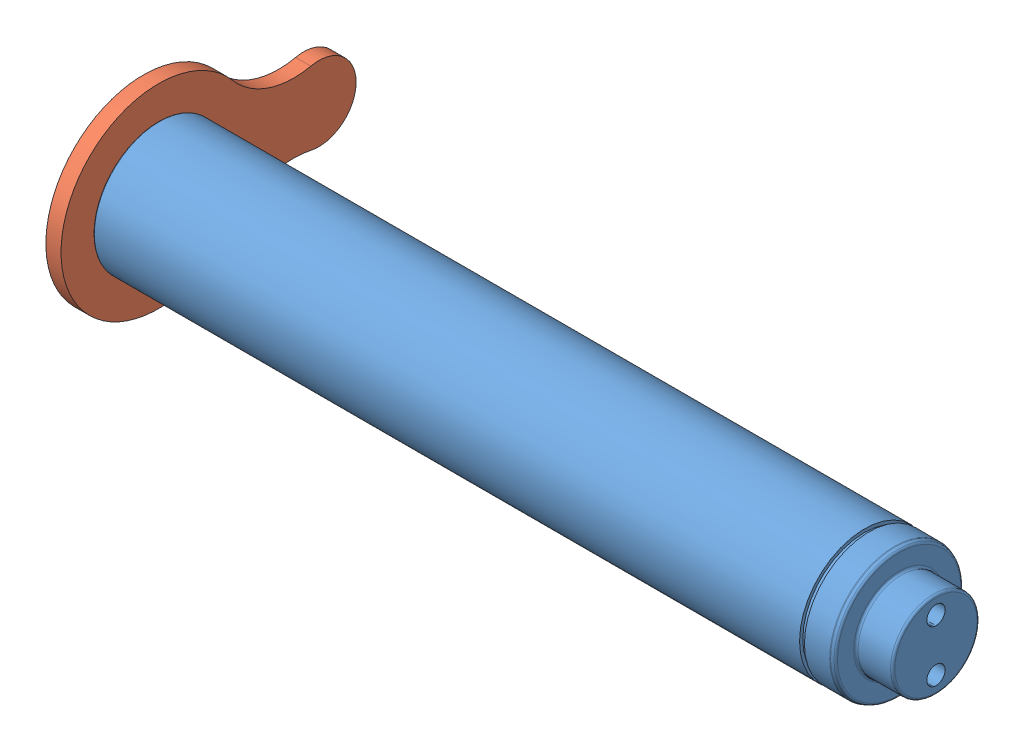
SolidWorks assembly 6344204, configuration Default. Lengths in mm.
Overall size (366 90 136.25).
3 component instances, 3 part files, 6 mates.
Components (placement in the parent):
- 6344205-1: 6344205 [Default] at origin size (364 60 60)
- 6342203-1: 6342203 [Default] at (-170 0 0) x (0 0 -1) z (1 0 0) size (136.25 90 7)
- Prop1_akselender-1: Prop1_akselender [Default] at (-171.1732 0 0) x (1 0 0) z (0 0 -1) (suppressed, hidden)
Mates (geometry in assembly coordinates):
- Coincident5: coincident anti-aligned: plane of 6344205-1 through (-163 29.6 0) normal (-1 0 0); plane of 6342203-1 through (-163 26.3702 -68.2248) normal (1 0 0)
- Concentric3: concentric aligned: cylinder of 6344205-1 through (-168 0 0) axis (-1 0 0) radius 28; cylinder of 6342203-1 through (-163 0 0) axis (-1 0 0) radius 28.25
- Parallel3: parallel aligned: plane of 6342203-1 through (-170 0 0) normal (0 1 0); plane of assembly through (0 0 0) normal (0 1 0)
- Concentric4: concentric aligned: cylinder of 6344205-1 through (-168 0 0) axis (-1 0 0) radius 5.1; cylinder of assembly through (-171.1732 0 0) axis (-1 0 0) radius 5.25
- Tangent3: tangent: plane of assembly through (-170 29.9582 -71.8487) normal (-1 0 0)
- Parallel4: parallel: plane of ?; plane of assembly through (0 0 0) normal (0 0 1)
